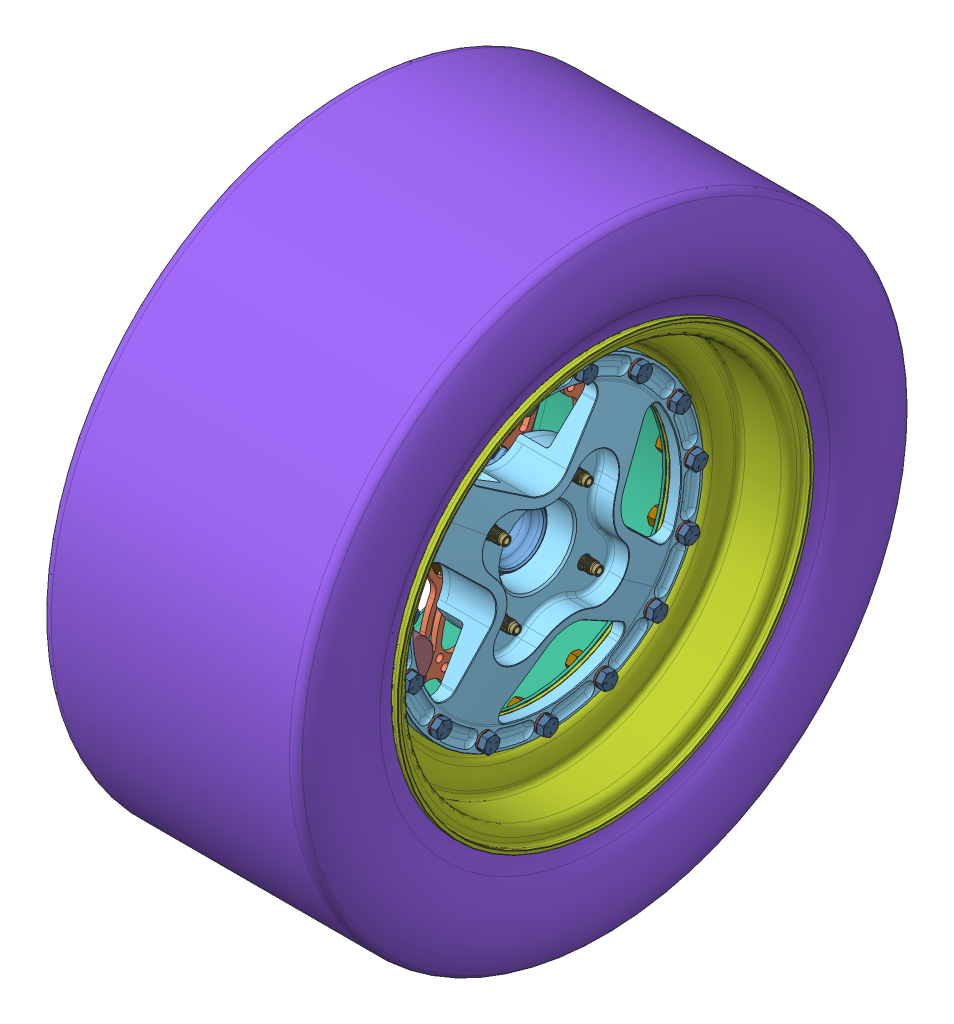
SolidWorks assembly Rear Hub Assembly, configuration Default. Lengths in mm.
Overall size (238.76 734.27 734.27).
97 component instances, 19 part files, 19 mates.
Components (placement in the parent):
- Rear Hub-1: Rear Hub [Default] at (-54.1741 65.8669 98.2203) x (1 0 0) z (0 0.614055 0.789263) size (98.29 117.35 117.35)
- Brake Rotor-1: Brake Rotor [Default] at (40.6949 65.8669 98.2203) x (0 -0.376494 0.926419) z (-1 0 0) size (227.12 227.12 4.57)
- Brake Rotor Pin-5: Brake Rotor Pin [Default] at (34.8529 100.1979 71.5105) x (1 0 0) z (0 0.524287 0.851542) size (8.93 13.97 13.97)
- Brake Rotor Snap Ring-2: Brake Rotor Snap Ring [Default] at (41.876 100.1979 71.5105) x (1 0 0) z (0 -0.608255 -0.793742) size (0.64 12.88 11.47)
- Brake Rotor Snap Ring-7: Brake Rotor Snap Ring [Default] at (41.876 59.901 55.1339) x (1 0 0) z (0 -0.991528 0.129894) size (0.64 12.88 11.47)
- Brake Rotor Snap Ring-8: Brake Rotor Snap Ring [Default] at (41.876 25.57 81.8438) x (1 0 0) z (0 -0.383273 0.923635) size (0.64 12.88 11.47)
- Brake Rotor Snap Ring-9: Brake Rotor Snap Ring [Default] at (41.876 31.5359 124.9302) x (1 0 0) z (0 0.608255 0.793742) size (0.64 12.88 11.47)
- Brake Rotor Snap Ring-10: Brake Rotor Snap Ring [Default] at (41.876 71.8328 141.3068) x (1 0 0) z (0 0.991528 -0.129894) size (0.64 12.88 11.47)
- Brake Rotor Snap Ring-11: Brake Rotor Snap Ring [Default] at (41.876 106.1638 114.5969) x (1 0 0) z (0 0.383273 -0.923635) size (0.64 12.88 11.47)
- Brake Rotor Pin-7: Brake Rotor Pin [Default] at (34.8529 59.901 55.1339) x (1 0 0) z (0 0.9996 -0.028274) size (8.93 13.97 13.97)
- Brake Rotor Pin-8: Brake Rotor Pin [Default] at (34.8529 25.57 81.8438) x (1 0 0) z (0 0.475314 -0.879816) size (8.93 13.97 13.97)
- Brake Rotor Pin-9: Brake Rotor Pin [Default] at (34.8529 31.5359 124.9302) x (1 0 0) z (0 -0.524287 -0.851542) size (8.93 13.97 13.97)
- Brake Rotor Pin-10: Brake Rotor Pin [Default] at (34.8529 71.8328 141.3068) x (1 0 0) z (0 -0.9996 0.028274) size (8.93 13.97 13.97)
- Brake Rotor Pin-11: Brake Rotor Pin [Default] at (34.8529 106.1638 114.5969) x (1 0 0) z (0 -0.475314 0.879816) size (8.93 13.97 13.97)
- Rear Wheel-1: Rear Wheel [Default] at (114.7359 65.8669 98.2203) x (0 -0.614055 -0.789263) z (1 0 0) size (523.24 523.24 238.76)
  - Rear Center-1: Rear Center [Default] at origin size (266.7 266.7 48.96)
  - Rear Inner Rim-1: Rear Inner Rim [Default] at (0 0 -31.75) x (0 0 -1) z (1 0 0) size (160.02 355.6 355.6)
  - Rear Outer Rim-1: Rear Outer Rim [Default] at (0 0 -31.75) size (355.6 355.6 62.86)
  - Rear Tire-1: Rear Tire [Default] at (0 0 -78.994) x (0 0 1) z (-1 0 0) size (238.76 523.24 523.24)
  - Steel Hex 5_16-18 Grade 5-1: Steel Hex 5_16-18 Grade 5 [95462A030] at (0 123.825 -40.0129) size (12.7 14.66 8.63)
  - Steel Hex 5_16in-18 1in Grade 5-1: Steel Hex 5_16in-18 1in Grade 5 [92865A583] at (0 123.825 -27.2574) x (0 0 -1) z (1 0 0) size (31.64 14.66 12.7)
  - 5_16 Small OD Washer-1: 5_16 Small OD Washer [Default] at (0 123.825 -19.05) x (1 0 0) z (0 -1 0) size (14.22 1.72 14.22)
  - 5_16 Small OD Washer-2: 5_16 Small OD Washer [Default] at (0 123.825 -36.6395) x (1 0 0) z (0 -1 0) size (14.22 1.72 14.22)
  - 5_16 Small OD Washer-3: 5_16 Small OD Washer [Default] at (50.3642 113.1198 -36.6395) x (0.913545 -0.406737 0) z (-0.406737 -0.913545 0) size (14.22 1.72 14.22)
  - 5_16 Small OD Washer-4: 5_16 Small OD Washer [Default] at (92.0199 82.8551 -36.6395) x (0.669131 -0.743145 0) z (-0.743145 -0.669131 0) size (14.22 1.72 14.22)
  - 5_16 Small OD Washer-5: 5_16 Small OD Washer [Default] at (117.7646 38.264 -36.6395) x (0.309017 -0.951057 0) z (-0.951057 -0.309017 0) size (14.22 1.72 14.22)
  - 5_16 Small OD Washer-6: 5_16 Small OD Washer [Default] at (123.1467 -12.9432 -36.6395) x (-0.104528 -0.994522 0) z (-0.994522 0.104528 0) size (14.22 1.72 14.22)
  - 5_16 Small OD Washer-7: 5_16 Small OD Washer [Default] at (107.2356 -61.9125 -36.6395) x (-0.5 -0.866025 0) z (-0.866025 0.5 0) size (14.22 1.72 14.22)
  - 5_16 Small OD Washer-8: 5_16 Small OD Washer [Default] at (72.7825 -100.1765 -36.6395) x (-0.809017 -0.587785 0) z (-0.587785 0.809017 0) size (14.22 1.72 14.22)
  - 5_16 Small OD Washer-9: 5_16 Small OD Washer [Default] at (25.7447 -121.1191 -36.6395) x (-0.978148 -0.207912 0) z (-0.207912 0.978148 0) size (14.22 1.72 14.22)
  - 5_16 Small OD Washer-10: 5_16 Small OD Washer [Default] at (-25.7447 -121.1191 -36.6395) x (-0.978148 0.207912 0) z (0.207912 0.978148 0) size (14.22 1.72 14.22)
  - 5_16 Small OD Washer-11: 5_16 Small OD Washer [Default] at (-72.7825 -100.1765 -36.6395) x (-0.809017 0.587785 0) z (0.587785 0.809017 0) size (14.22 1.72 14.22)
  - 5_16 Small OD Washer-12: 5_16 Small OD Washer [Default] at (-107.2356 -61.9125 -36.6395) x (-0.5 0.866025 0) z (0.866025 0.5 0) size (14.22 1.72 14.22)
  - 5_16 Small OD Washer-13: 5_16 Small OD Washer [Default] at (-123.1467 -12.9432 -36.6395) x (-0.104528 0.994522 0) z (0.994522 0.104528 0) size (14.22 1.72 14.22)
  - 5_16 Small OD Washer-14: 5_16 Small OD Washer [Default] at (-117.7646 38.264 -36.6395) x (0.309017 0.951057 0) z (0.951057 -0.309017 0) size (14.22 1.72 14.22)
  - 5_16 Small OD Washer-15: 5_16 Small OD Washer [Default] at (-92.0199 82.8551 -36.6395) x (0.669131 0.743145 0) z (0.743145 -0.669131 0) size (14.22 1.72 14.22)
  - 5_16 Small OD Washer-16: 5_16 Small OD Washer [Default] at (-50.3642 113.1198 -36.6395) x (0.913545 0.406737 0) z (0.406737 -0.913545 0) size (14.22 1.72 14.22)
  - 5_16 Small OD Washer-17: 5_16 Small OD Washer [Default] at (50.3642 113.1198 -19.05) x (0.913545 -0.406737 0) z (-0.406737 -0.913545 0) size (14.22 1.72 14.22)
  - 5_16 Small OD Washer-18: 5_16 Small OD Washer [Default] at (92.0199 82.8551 -19.05) x (0.669131 -0.743145 0) z (-0.743145 -0.669131 0) size (14.22 1.72 14.22)
  - 5_16 Small OD Washer-19: 5_16 Small OD Washer [Default] at (117.7646 38.264 -19.05) x (0.309017 -0.951057 0) z (-0.951057 -0.309017 0) size (14.22 1.72 14.22)
  - 5_16 Small OD Washer-20: 5_16 Small OD Washer [Default] at (123.1467 -12.9432 -19.05) x (-0.104528 -0.994522 0) z (-0.994522 0.104528 0) size (14.22 1.72 14.22)
  - 5_16 Small OD Washer-21: 5_16 Small OD Washer [Default] at (107.2356 -61.9125 -19.05) x (-0.5 -0.866025 0) z (-0.866025 0.5 0) size (14.22 1.72 14.22)
  - 5_16 Small OD Washer-22: 5_16 Small OD Washer [Default] at (72.7825 -100.1765 -19.05) x (-0.809017 -0.587785 0) z (-0.587785 0.809017 0) size (14.22 1.72 14.22)
  - 5_16 Small OD Washer-23: 5_16 Small OD Washer [Default] at (25.7447 -121.1191 -19.05) x (-0.978148 -0.207912 0) z (-0.207912 0.978148 0) size (14.22 1.72 14.22)
  - 5_16 Small OD Washer-24: 5_16 Small OD Washer [Default] at (-25.7447 -121.1191 -19.05) x (-0.978148 0.207912 0) z (0.207912 0.978148 0) size (14.22 1.72 14.22)
  - 5_16 Small OD Washer-25: 5_16 Small OD Washer [Default] at (-72.7825 -100.1765 -19.05) x (-0.809017 0.587785 0) z (0.587785 0.809017 0) size (14.22 1.72 14.22)
  - 5_16 Small OD Washer-26: 5_16 Small OD Washer [Default] at (-107.2356 -61.9125 -19.05) x (-0.5 0.866025 0) z (0.866025 0.5 0) size (14.22 1.72 14.22)
  - 5_16 Small OD Washer-27: 5_16 Small OD Washer [Default] at (-123.1467 -12.9432 -19.05) x (-0.104528 0.994522 0) z (0.994522 0.104528 0) size (14.22 1.72 14.22)
  - 5_16 Small OD Washer-28: 5_16 Small OD Washer [Default] at (-117.7646 38.264 -19.05) x (0.309017 0.951057 0) z (0.951057 -0.309017 0) size (14.22 1.72 14.22)
  - 5_16 Small OD Washer-29: 5_16 Small OD Washer [Default] at (-92.0199 82.8551 -19.05) x (0.669131 0.743145 0) z (0.743145 -0.669131 0) size (14.22 1.72 14.22)
  - 5_16 Small OD Washer-30: 5_16 Small OD Washer [Default] at (-50.3642 113.1198 -19.05) x (0.913545 0.406737 0) z (0.406737 -0.913545 0) size (14.22 1.72 14.22)
  - Steel Hex 5_16in-18 1in Grade 5-2: Steel Hex 5_16in-18 1in Grade 5 [92865A583] at (50.3642 113.1198 -27.2574) x (0 0 -1) z (0.913545 -0.406737 0) size (31.64 14.66 12.7)
  - Steel Hex 5_16in-18 1in Grade 5-3: Steel Hex 5_16in-18 1in Grade 5 [92865A583] at (92.0199 82.8551 -27.2574) x (0 0 -1) z (0.669131 -0.743145 0) size (31.64 14.66 12.7)
  - Steel Hex 5_16in-18 1in Grade 5-4: Steel Hex 5_16in-18 1in Grade 5 [92865A583] at (117.7646 38.264 -27.2574) x (0 0 -1) z (0.309017 -0.951057 0) size (31.64 14.66 12.7)
  - Steel Hex 5_16in-18 1in Grade 5-5: Steel Hex 5_16in-18 1in Grade 5 [92865A583] at (123.1467 -12.9432 -27.2574) x (0 0 -1) z (-0.104528 -0.994522 0) size (31.64 14.66 12.7)
  - Steel Hex 5_16in-18 1in Grade 5-6: Steel Hex 5_16in-18 1in Grade 5 [92865A583] at (107.2356 -61.9125 -27.2574) x (0 0 -1) z (-0.5 -0.866025 0) size (31.64 14.66 12.7)
  - Steel Hex 5_16in-18 1in Grade 5-7: Steel Hex 5_16in-18 1in Grade 5 [92865A583] at (72.7825 -100.1765 -27.2574) x (0 0 -1) z (-0.809017 -0.587785 0) size (31.64 14.66 12.7)
  - Steel Hex 5_16in-18 1in Grade 5-8: Steel Hex 5_16in-18 1in Grade 5 [92865A583] at (25.7447 -121.1191 -27.2574) x (0 0 -1) z (-0.978148 -0.207912 0) size (31.64 14.66 12.7)
  - Steel Hex 5_16in-18 1in Grade 5-9: Steel Hex 5_16in-18 1in Grade 5 [92865A583] at (-25.7447 -121.1191 -27.2574) x (0 0 -1) z (-0.978148 0.207912 0) size (31.64 14.66 12.7)
  - Steel Hex 5_16in-18 1in Grade 5-10: Steel Hex 5_16in-18 1in Grade 5 [92865A583] at (-72.7825 -100.1765 -27.2574) x (0 0 -1) z (-0.809017 0.587785 0) size (31.64 14.66 12.7)
  - Steel Hex 5_16in-18 1in Grade 5-11: Steel Hex 5_16in-18 1in Grade 5 [92865A583] at (-107.2356 -61.9125 -27.2574) x (0 0 -1) z (-0.5 0.866025 0) size (31.64 14.66 12.7)
  - Steel Hex 5_16in-18 1in Grade 5-12: Steel Hex 5_16in-18 1in Grade 5 [92865A583] at (-123.1467 -12.9432 -27.2574) x (0 0 -1) z (-0.104528 0.994522 0) size (31.64 14.66 12.7)
  - Steel Hex 5_16in-18 1in Grade 5-13: Steel Hex 5_16in-18 1in Grade 5 [92865A583] at (-117.7646 38.264 -27.2574) x (0 0 -1) z (0.309017 0.951057 0) size (31.64 14.66 12.7)
  - Steel Hex 5_16in-18 1in Grade 5-14: Steel Hex 5_16in-18 1in Grade 5 [92865A583] at (-92.0199 82.8551 -27.2574) x (0 0 -1) z (0.669131 0.743145 0) size (31.64 14.66 12.7)
  - Steel Hex 5_16in-18 1in Grade 5-15: Steel Hex 5_16in-18 1in Grade 5 [92865A583] at (-50.3642 113.1198 -27.2574) x (0 0 -1) z (0.913545 0.406737 0) size (31.64 14.66 12.7)
  - Steel Hex 5_16-18 Grade 5-2: Steel Hex 5_16-18 Grade 5 [95462A030] at (50.3642 113.1198 -40.0129) x (0.913545 -0.406737 0) z (0 0 1) size (12.7 14.66 8.63)
  - Steel Hex 5_16-18 Grade 5-3: Steel Hex 5_16-18 Grade 5 [95462A030] at (92.0199 82.8551 -40.0129) x (0.669131 -0.743145 0) z (0 0 1) size (12.7 14.66 8.63)
  - Steel Hex 5_16-18 Grade 5-4: Steel Hex 5_16-18 Grade 5 [95462A030] at (117.7646 38.264 -40.0129) x (0.309017 -0.951057 0) z (0 0 1) size (12.7 14.66 8.63)
  - Steel Hex 5_16-18 Grade 5-5: Steel Hex 5_16-18 Grade 5 [95462A030] at (123.1467 -12.9432 -40.0129) x (-0.104528 -0.994522 0) z (0 0 1) size (12.7 14.66 8.63)
  - Steel Hex 5_16-18 Grade 5-6: Steel Hex 5_16-18 Grade 5 [95462A030] at (107.2356 -61.9125 -40.0129) x (-0.5 -0.866025 0) z (0 0 1) size (12.7 14.66 8.63)
  - Steel Hex 5_16-18 Grade 5-7: Steel Hex 5_16-18 Grade 5 [95462A030] at (72.7825 -100.1765 -40.0129) x (-0.809017 -0.587785 0) z (0 0 1) size (12.7 14.66 8.63)
  - Steel Hex 5_16-18 Grade 5-8: Steel Hex 5_16-18 Grade 5 [95462A030] at (25.7447 -121.1191 -40.0129) x (-0.978148 -0.207912 0) z (0 0 1) size (12.7 14.66 8.63)
  - Steel Hex 5_16-18 Grade 5-9: Steel Hex 5_16-18 Grade 5 [95462A030] at (-25.7447 -121.1191 -40.0129) x (-0.978148 0.207912 0) z (0 0 1) size (12.7 14.66 8.63)
  - Steel Hex 5_16-18 Grade 5-10: Steel Hex 5_16-18 Grade 5 [95462A030] at (-72.7825 -100.1765 -40.0129) x (-0.809017 0.587785 0) z (0 0 1) size (12.7 14.66 8.63)
  - Steel Hex 5_16-18 Grade 5-11: Steel Hex 5_16-18 Grade 5 [95462A030] at (-107.2356 -61.9125 -40.0129) x (-0.5 0.866025 0) z (0 0 1) size (12.7 14.66 8.63)
  - Steel Hex 5_16-18 Grade 5-12: Steel Hex 5_16-18 Grade 5 [95462A030] at (-123.1467 -12.9432 -40.0129) x (-0.104528 0.994522 0) z (0 0 1) size (12.7 14.66 8.63)
  - Steel Hex 5_16-18 Grade 5-13: Steel Hex 5_16-18 Grade 5 [95462A030] at (-117.7646 38.264 -40.0129) x (0.309017 0.951057 0) z (0 0 1) size (12.7 14.66 8.63)
  - Steel Hex 5_16-18 Grade 5-14: Steel Hex 5_16-18 Grade 5 [95462A030] at (-92.0199 82.8551 -40.0129) x (0.669131 0.743145 0) z (0 0 1) size (12.7 14.66 8.63)
  - Steel Hex 5_16-18 Grade 5-15: Steel Hex 5_16-18 Grade 5 [95462A030] at (-50.3642 113.1198 -40.0129) x (0.913545 0.406737 0) z (0 0 1) size (12.7 14.66 8.63)
- Titanium Stud-1: Titanium Stud [Default] at (50.2834 105.3301 67.5176) x (1 0 0) z (0 0.614055 0.789263) size (50.8 12.7 12.7)
- Titanium Stud-2: Titanium Stud [Default] at (50.2834 35.1642 58.7573) x (1 0 0) z (0 0.789263 -0.614055) size (50.8 12.7 12.7)
- Titanium Stud-3: Titanium Stud [Default] at (50.2834 26.4038 128.9231) x (1 0 0) z (0 -0.614055 -0.789263) size (50.8 12.7 12.7)
- Titanium Stud-4: Titanium Stud [Default] at (50.2834 96.5697 137.6835) x (1 0 0) z (0 -0.789263 0.614055) size (50.8 12.7 12.7)
- Brake Caliper-2: Brake Caliper [Default] at (17.0994 -0.3856 162.6551) x (0 -0.854037 -0.520212) z (-1 0 0) size (101.75 67.09 67.01)
  - Brake Caliper Frame-1: Brake Caliper Frame [Default] at origin size (101.75 67.09 67.01)
  - Brake Pad-1: Brake Pad [Default] at (-23.5554 37.6919 -13.7004) x (0.999992 0.003877 0) z (0 0 1) size (67.93 44.48 7.61)
  - Brake Pad-2: Brake Pad [Default] at (-23.5554 37.6919 -29.2996) x (-0.999992 -0.003877 0) z (0 0 -1) size (67.93 44.48 7.61)
  - Brake Pin-1: Brake Pin [Default] at (-23.5554 37.6919 -26.0423) x (0 0 1) z (0.999547 0.030097 0) size (39.8 8.85 8.85)
- Rear Upright Bearing-1: Rear Upright Bearing [Default] at (13.7709 65.8669 98.2203) x (1 0 0) z (0 -0.168851 0.985642) size (19.05 116.17 118.54) (flexible)
  - Rear Cup-1: Rear Cup [Default] at origin size (15.08 94.46 94.46)
  - Rear Cone-1: Rear Cone [Default] x (1 0 0) z (0 -0.643649 -0.765321) size (19.05 79.33 79.33)
  - Rear Rollers-1: Rear Rollers [Default] x (1 0 0) z (0 -0.643649 -0.765321) size (15.2 88.88 88.79)
- Rear Upright Bearing-2: Rear Upright Bearing [Default] at (-19.2735 65.8669 98.2203) x (-1 0 0) z (0 0.184171 -0.982894) size (19.05 115.65 118.97) (flexible)
  - Rear Cup-1: Rear Cup [Default] at origin size (15.08 94.46 94.46)
  - Rear Cone-1: Rear Cone [Default] x (1 0 0) z (0 0.713655 0.700497) size (19.05 79.33 79.33)
  - Rear Rollers-1: Rear Rollers [Default] x (1 0 0) z (0 0.713655 0.700497) size (15.2 88.88 88.79)
- Rear Hub Nut-2: Rear Hub Nut [Default] at (-51.0235 65.8669 98.2203) x (1 0 0) z (0 0.614055 0.789263) size (14.61 79.38 79.38)
Mates (geometry in assembly coordinates):
- Concentric1: concentric aligned: cylinder of Rear Hub-1 through (46.9179 100.1979 71.5105) axis (-1 0 0) radius 5.3975; cylinder of Brake Rotor Pin-5 through (34.8529 100.1979 71.5105) axis (-1 0 0) radius 5.3721
- Concentric2: concentric aligned: cylinder of Brake Rotor Snap Ring-2 through (42.1935 100.1979 71.5105) axis (-1 0 0) radius 4.6482; cylinder of Brake Rotor Pin-5 through (34.8529 100.1979 71.5105) axis (-1 0 0) radius 4.8514
- Coincident1: coincident anti-aligned: plane of Brake Rotor Snap Ring-2 through (42.1935 100.1979 71.5105) normal (1 0 0); plane of Brake Rotor Pin-5 through (42.1935 104.329 68.9669) normal (-1 0 0)
- Concentric3: concentric anti-aligned: cylinder of Brake Rotor-1 through (36.1229 106.1638 114.5969) axis (1 0 0) radius 5.4356; cylinder of Brake Rotor Pin-11 through (34.8529 106.1638 114.5969) axis (-1 0 0) radius 5.3721
- Concentric4: concentric anti-aligned: cylinder of Brake Rotor-1 through (36.1229 100.1979 71.5105) axis (1 0 0) radius 5.4356; cylinder of Brake Rotor Pin-5 through (34.8529 100.1979 71.5105) axis (-1 0 0) radius 5.3721
- Concentric5: concentric anti-aligned: cylinder of Titanium Stud-1 through (50.2834 105.3301 67.5176) axis (-1 0 0) radius 3.81; cylinder of Rear Hub-1 through (49.3309 105.3301 67.5176) axis (1 0 0) radius 5.08
- Coincident2: coincident anti-aligned: plane of Rear Hub-1 through (51.8709 87.9189 81.0636) normal (-1 0 0); plane of Titanium Stud-1 through (51.8709 110.3419 63.6183) normal (1 0 0)
- Coincident3: coincident anti-aligned: plane of Rear Hub-1 through (60.1259 112.1761 62.1913) normal (1 0 0); plane of Rear Wheel-1/Rear Center-1 through (60.1259 65.8669 98.2203) normal (-1 0 0)
- Concentric6: concentric aligned: cylinder of Rear Hub-1 through (-54.1741 65.8669 98.2203) axis (-1 0 0) radius 31.75; cylinder of Rear Wheel-1/Rear Tire-1 through (12.5631 65.8669 98.2203) axis (-1 0 0) radius 261.62
- Concentric7: concentric aligned: cylinder of Rear Wheel-1/Rear Center-1 through (108.8656 35.1642 58.7573) axis (-1 0 0) radius 5.08; cylinder of Titanium Stud-2 through (50.2834 35.1642 58.7573) axis (-1 0 0) radius 2.3813
- Coincident6: coincident anti-aligned: plane of Rear Hub-1; plane of Brake Caliper-2/Brake Caliper Frame-1 through (38.5994 -0.3856 162.6551) normal (1 0 0)
- Concentric8: concentric aligned: circle of Brake Rotor-1; circle of Brake Caliper-2/Brake Pad-1
- Concentric9: concentric aligned: cylinder of Rear Hub-1 through (-54.1741 65.8669 98.2203) axis (-1 0 0) radius 31.75; cylinder of Rear Upright Bearing-1/Rear Cone-1 through (31.2969 65.8669 98.2203) axis (-1 0 0) radius 31.75
- Concentric10: concentric anti-aligned: cylinder of Rear Hub-1 through (-54.1741 65.8669 98.2203) axis (-1 0 0) radius 31.75; cylinder of ? through (-36.7995 65.8669 98.2203) axis (1 0 0) radius 31.75
- Coincident8: coincident anti-aligned: plane of Rear Hub-1 through (32.8209 92.1288 77.7883) normal (-1 0 0); plane of Rear Upright Bearing-1/Rear Cone-1 through (32.8209 47.4428 66.7461) normal (1 0 0)
- Concentric13: concentric anti-aligned: cylinder of Rear Hub-1 through (-54.1741 65.8669 98.2203) axis (-1 0 0) radius 31.75; circle of Rear Hub Nut-2
- Coincident9: coincident anti-aligned: plane of ? through (-38.3235 96.1539 77.9035) normal (-1 0 0); plane of Rear Hub Nut-2 through (-38.3235 97.1908 73.85) normal (1 0 0)
- Coincident10: coincident anti-aligned: plane of Rear Hub-1 through (36.1229 94.6849 75.7996) normal (-1 0 0); plane of Brake Rotor Pin-5 through (36.1229 106.1459 67.8483) normal (1 0 0)
- Coincident12: coincident anti-aligned: plane of Brake Rotor-1 through (36.1229 65.8669 98.2203) normal (-1 0 0); plane of Brake Rotor Pin-5 through (36.1229 106.1459 67.8483) normal (1 0 0)
